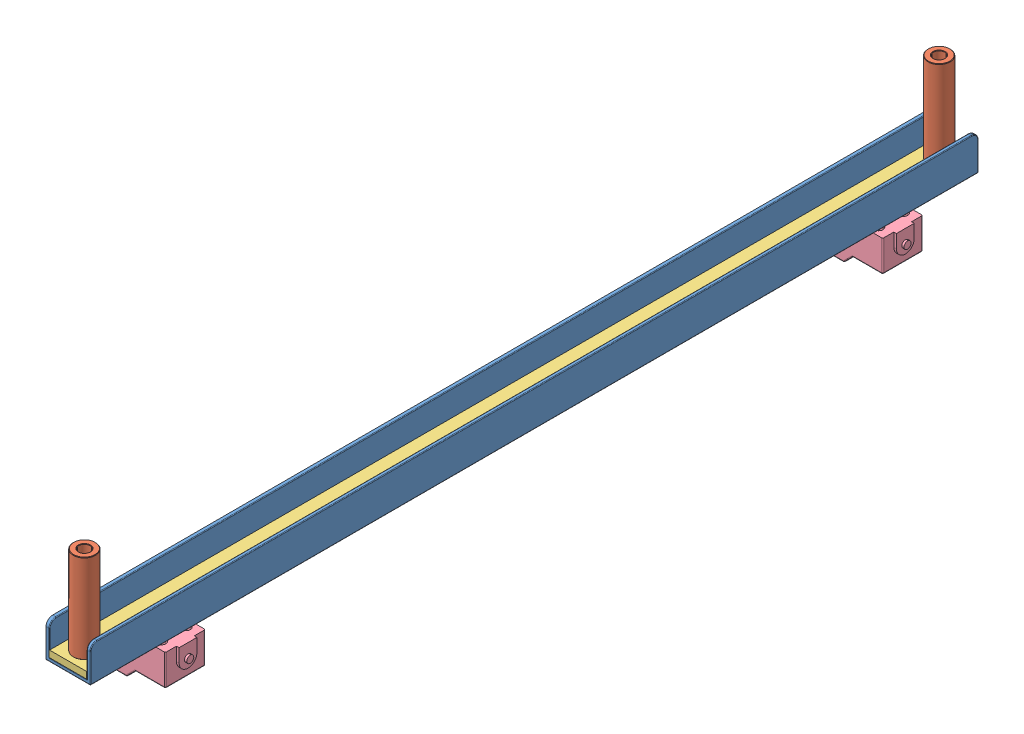
SolidWorks assembly drag chane center bed all, configuration Default. Lengths in mm.
Overall size (38.22 62.7 400).
10 component instances, 5 part files, 24 mates.
Components (placement in the parent):
- drag chain angel bed-1: drag chain angel bed [Default] at (111.2967 209.0447 116.1752) size (20 16 400)
- Aluminum Spacer 40mm-1: Aluminum Spacer 40mm [Default] at (121.0947 253.6447 508.6752) x (1 0 0) z (0 -1 0) size (10 10 40)
- Aluminum Spacer 40mm-2: Aluminum Spacer 40mm [Default] at (121.0947 253.6447 123.6752) x (1 0 0) z (0 -1 0) size (10 10 40)
- rubber bed-1: rubber bed [Default] at (121.0947 210.6447 316.1752) x (0 0 -1) z (1 0 0) size (400 3 16.8)
- SN04-N-2: SN04-N [По умолчанию] at (50.88 223.424 145.3333) x (-1 0 0) z (0 0 1) size (38.22 18.1 18)
- SN04-N-3: SN04-N [По умолчанию] at (50.88 223.424 468.4586) x (-1 0 0) z (0 0 1) size (38.22 18.1 18)
- Hexagon socket head cap screw, slim head-1: Hexagon socket head cap screw, slim head [Default] at (124.2967 210.6447 148.7833) x (1 0 0) z (0 1 0) size (7 7 14.8)
- Hexagon socket head cap screw, slim head-2: Hexagon socket head cap screw, slim head [Default] at (124.2967 210.6447 159.8833) x (1 0 0) z (0 1 0) size (7 7 14.8)
- Hexagon socket head cap screw, slim head-3: Hexagon socket head cap screw, slim head [Default] at (124.2967 210.6447 483.0086) x (1 0 0) z (0 1 0) size (7 7 14.8)
- Hexagon socket head cap screw, slim head-4: Hexagon socket head cap screw, slim head [Default] at (124.2967 210.6447 471.9086) x (1 0 0) z (0 1 0) size (7 7 14.8)
Mates (geometry in assembly coordinates):
- Concentric1: concentric anti-aligned: cylinder of drag chain angel bed-1 through (121.0947 209.0437 508.6752) axis (0 1 0) radius 2.55; cylinder of rubber bed-1 through (121.0947 213.6447 508.6752) axis (0 -1 0) radius 2.55
- Coincident1: coincident anti-aligned: plane of drag chain angel bed-1 through (112.8967 210.6447 516.1752) normal (0 1 0); plane of rubber bed-1 through (121.0947 210.6447 316.1752) normal (0 -1 0)
- Coincident2: coincident anti-aligned: plane of Aluminum Spacer 40mm-1 through (121.0947 213.6447 508.6752) normal (0 -1 0); plane of rubber bed-1 through (121.0947 213.6447 316.1752) normal (0 1 0)
- Concentric3: concentric aligned: cylinder of Aluminum Spacer 40mm-1 through (121.0947 213.6447 508.6752) axis (0 1 0) radius 2.55; cylinder of drag chain angel bed-1 through (121.0947 209.0437 508.6752) axis (0 1 0) radius 2.55
- Concentric4: concentric anti-aligned: cylinder of Aluminum Spacer 40mm-1 through (121.0947 213.6447 508.6752) axis (0 1 0) radius 2.55; cylinder of rubber bed-1 through (121.0947 213.6447 508.6752) axis (0 -1 0) radius 2.55
- Concentric5: concentric aligned: cylinder of Aluminum Spacer 40mm-2 through (121.0947 213.6447 123.6752) axis (0 1 0) radius 2.55; cylinder of drag chain angel bed-1 through (121.0947 209.0437 123.6752) axis (0 1 0) radius 2.55
- Concentric6: concentric anti-aligned: cylinder of Aluminum Spacer 40mm-2 through (121.0947 213.6447 123.6752) axis (0 1 0) radius 2.55; cylinder of rubber bed-1 through (121.0947 213.6447 123.6752) axis (0 -1 0) radius 2.55
- Coincident3: coincident anti-aligned: plane of Aluminum Spacer 40mm-2 through (121.0947 213.6447 123.6752) normal (0 -1 0); plane of rubber bed-1 through (121.0947 213.6447 316.1752) normal (0 1 0)
- Coincident9: coincident anti-aligned: plane of drag chain angel bed-1 through (131.2967 209.0447 516.1752) normal (0 -1 0); plane of SN04-N-2 through (135.3467 209.0447 163.3333) normal (0 1 0)
- Coincident11: coincident anti-aligned: plane of drag chain angel bed-1 through (131.2967 209.0447 516.1752) normal (0 -1 0); plane of SN04-N-3 through (135.3467 209.0447 486.4586) normal (0 1 0)
- Coincident13: coincident anti-aligned: plane of drag chain angel bed-1 through (131.2967 209.0447 516.1752) normal (0 -1 0); plane of SN04-N-3 through (135.3467 209.0447 486.4586) normal (0 1 0)
- Concentric16: concentric anti-aligned: cylinder of SN04-N-3 through (124.2967 212.8447 483.0086) axis (0 -1 0) radius 1.95; cylinder of Hexagon socket head cap screw, slim head-3 through (124.2967 213.4447 483.0086) axis (0 1 0) radius 2
- Coincident14: coincident anti-aligned: plane of drag chain angel bed-1 through (112.8967 210.6447 516.1752) normal (0 1 0); plane of Hexagon socket head cap screw, slim head-3 through (124.2967 210.6447 479.5086) normal (0 -1 0)
- Concentric17: concentric anti-aligned: cylinder of Hexagon socket head cap screw, slim head-1 through (124.2967 213.4447 148.7833) axis (0 1 0) radius 2; cylinder of SN04-N-2 through (124.2967 212.8447 148.7833) axis (0 -1 0) radius 1.95
- Coincident15: coincident anti-aligned: plane of drag chain angel bed-1 through (112.8967 210.6447 516.1752) normal (0 1 0); plane of Hexagon socket head cap screw, slim head-4 through (124.2967 210.6447 468.4086) normal (0 -1 0)
- Width5: width: plane of drag chain angel bed-1 through (122.2967 209.0437 491.1752) normal (1 0 0); plane of drag chain angel bed-1 through (126.2967 209.0437 491.1752) normal (-1 0 0); cylinder of Hexagon socket head cap screw, slim head-4 through (124.2967 213.4447 471.9086) axis (0 1 0) radius 2
- Width6: width: plane of drag chain angel bed-1 through (122.2967 209.0437 491.1752) normal (1 0 0); plane of drag chain angel bed-1 through (126.2967 209.0437 491.1752) normal (-1 0 0); cylinder of Hexagon socket head cap screw, slim head-3 through (124.2967 213.4447 483.0086) axis (0 1 0) radius 2
- Width7: width: plane of drag chain angel bed-1 through (122.2967 209.0437 141.1752) normal (1 0 0); plane of drag chain angel bed-1 through (126.2967 209.0437 141.1752) normal (-1 0 0); cylinder of Hexagon socket head cap screw, slim head-1 through (124.2967 213.4447 148.7833) axis (0 1 0) radius 2
- Concentric18: concentric anti-aligned: cylinder of SN04-N-2 through (124.2967 212.8447 159.8833) axis (0 -1 0) radius 1.95; cylinder of Hexagon socket head cap screw, slim head-2 through (124.2967 213.4447 159.8833) axis (0 1 0) radius 2
- Width8: width: plane of drag chain angel bed-1 through (122.2967 209.0437 141.1752) normal (1 0 0); plane of drag chain angel bed-1 through (126.2967 209.0437 141.1752) normal (-1 0 0); cylinder of Hexagon socket head cap screw, slim head-2 through (124.2967 213.4447 159.8833) axis (0 1 0) radius 2
- Width9: width: plane of drag chain angel bed-1 through (122.2967 209.0437 141.1752) normal (1 0 0); plane of drag chain angel bed-1 through (126.2967 209.0437 141.1752) normal (-1 0 0); cylinder of Hexagon socket head cap screw, slim head-1 through (124.2967 213.4447 148.7833) axis (0 1 0) radius 2
- Coincident16: coincident aligned: plane of Hexagon socket head cap screw, slim head-1 through (124.2967 210.6447 145.2833) normal (0 -1 0); plane of Hexagon socket head cap screw, slim head-2 through (124.2967 210.6447 156.3833) normal (0 -1 0)
- Coincident17: coincident anti-aligned: plane of Hexagon socket head cap screw, slim head-1 through (124.2967 210.6447 145.2833) normal (0 -1 0); plane of drag chain angel bed-1 through (112.8967 210.6447 516.1752) normal (0 1 0)
- Concentric19: concentric anti-aligned: cylinder of SN04-N-3 through (124.2967 212.8447 471.9086) axis (0 -1 0) radius 1.95; cylinder of Hexagon socket head cap screw, slim head-4 through (124.2967 213.4447 471.9086) axis (0 1 0) radius 2
